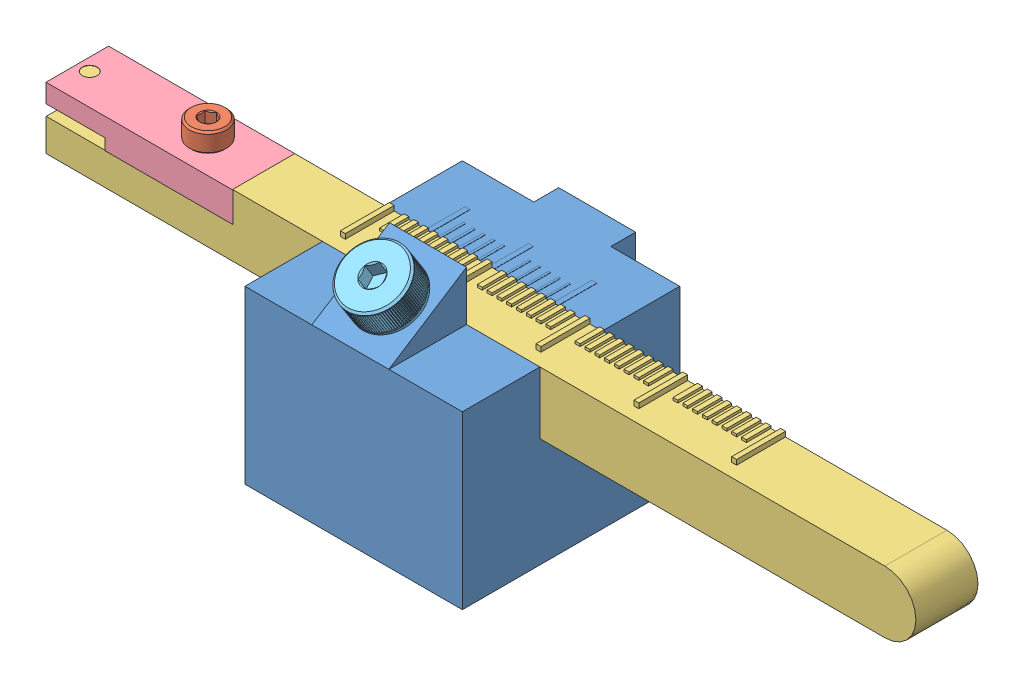
SolidWorks assembly headbar finished flipped (1), configuration Default. Lengths in mm.
Overall size (88.9 24.86 25.74).
6 component instances, 5 part files, 4 mates.
Components (placement in the parent):
- bar rest-1: bar rest [Default] at origin size (22.23 22.61 24.77)
- 91292A003_TYPE 18-8 SS SOCKET HEAD CAP SCREW-1: 91292A003_TYPE 18-8 SS SOCKET HEAD CAP SCREW [91292A003] at (-14.8888 5.7455 0) x (1 0 0) z (0 -1 0) size (3.8 3.8 5.09)
- headbar-1: headbar [Default] at (-76.8022 -57.3797 49.0764) x (0 0 -1) z (1 0 0) size (6.4 6.86 88.9)
  - headpost holder-1: headpost holder [Default] at (49.0764 62.9677 48.5529) x (0 1 0) z (0 0 1) size (6.86 6.35 88.9)
  - headbar clamp-1: headbar clamp [Default] at (49.0764 64.2202 58.1033) x (0 0 1) z (-1 0 0) size (19.1 3.05 6.4)
- 96125A301_NICKEL ALLOY SHOULDER SCREW-1: 96125A301_NICKEL ALLOY SHOULDER SCREW [96125A301] at (10.7798 13.9746 8.8593) x (0.978373 0.111501 -0.174221) z (0 0.842271 0.539054) size (6.35 6.35 10.69)
Mates (geometry in assembly coordinates):
- Concentric4: concentric anti-aligned: circle of 91292A003_TYPE 18-8 SS SOCKET HEAD CAP SCREW-1; circle of headbar-1/headbar clamp-1
- Coincident3: coincident anti-aligned: plane of 91292A003_TYPE 18-8 SS SOCKET HEAD CAP SCREW-1 through (-14.8888 8.7455 0) normal (0 -1 0); plane of headbar-1/headbar clamp-1 through (-18.6988 8.7455 0) normal (0 1 0)
- Concentric5: concentric anti-aligned: circle of bar rest-1; circle of 96125A301_NICKEL ALLOY SHOULDER SCREW-1
- Coincident6: coincident anti-aligned: plane of bar rest-1 through (-0.001 8.763 11.1125) normal (0 0.842271 0.539054); plane of 96125A301_NICKEL ALLOY SHOULDER SCREW-1 through (11.4365 9.626 9.7641) normal (0 -0.842271 -0.539054)
